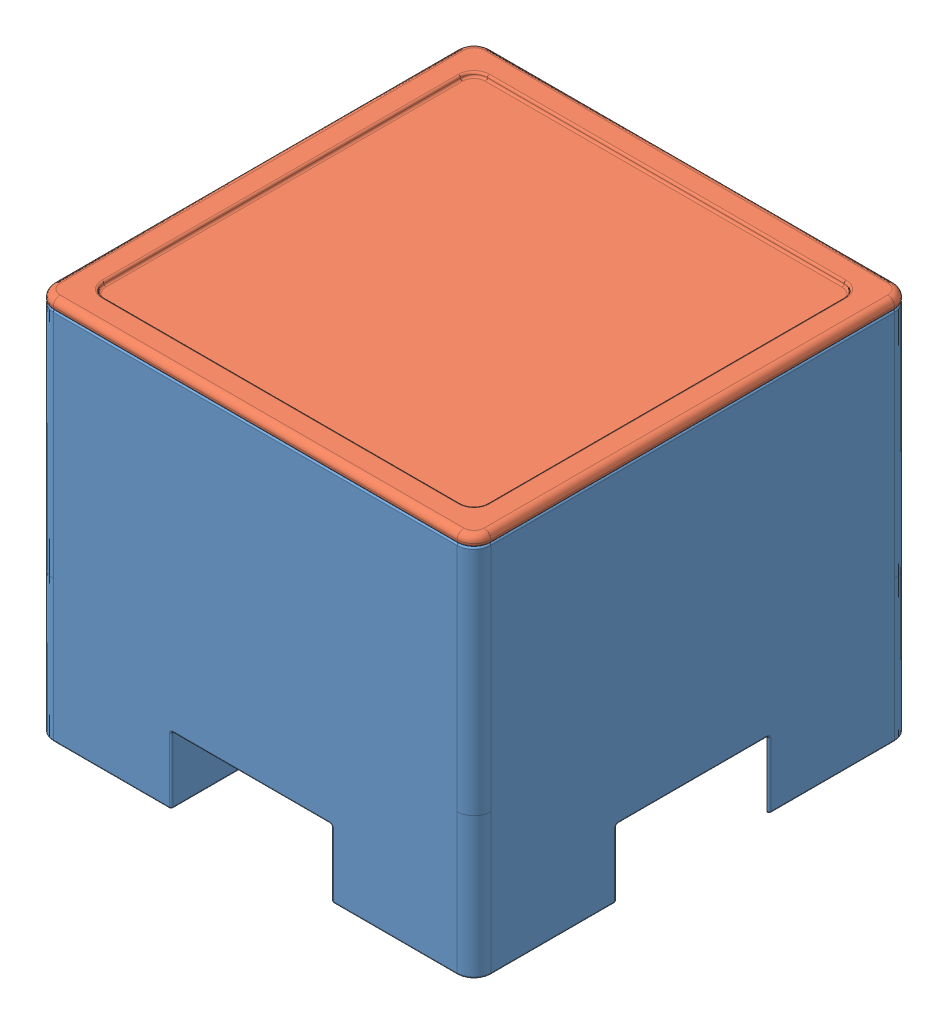
SolidWorks assembly Bloc programme, configuration Défaut. Lengths in mm.
Overall size (65 57 65).
2 component instances, 2 part files, 4 mates.
Components (placement in the parent):
- Blocprog Corps symetrie-1: Blocprog Corps symetrie [Défaut] at (0.5652 5.0087 2.1361) size (65 55.5 65)
- Couvercle-1: Couvercle [Défaut] at (0.5652 39.5087 2.1361) x (1 0 0) z (0 1 0) size (65 65 11.5)
Mates (geometry in assembly coordinates):
- Sur place1: in place: plane of assembly through (0 34.5 0) normal (0 1 0); plane of ? through (0 34.5 0) normal (0 1 0); moOrthogonalPlaneRef_w of assembly through (0 34.5 0) normal (0 1 0); plane of ? through (0 34.5 0) normal (0 0 -1); plane of assembly through (0 34.5 0) normal (0 1 0); line of ? through (-55 0 34.5) axis (0 1 0); plane of Blocprog Corps symetrie-1 through (0.5652 39.5087 2.1361) normal (0 1 0); unknown of Couvercle-1
- Coïncidente1: coincident: plane of Blocprog Corps symetrie-1; plane of Couvercle-1
- Coïncidente2: coincident: moOrthogonalPlaneRef_w of Blocprog Corps symetrie-1 through (0.5652 39.5087 2.1361) normal (0 0 -1); plane of Couvercle-1 through (0.5652 39.5087 2.1361) normal (0 0 -1)
- Coïncidente3: coincident: moOrthogonalPlaneRef_w of Blocprog Corps symetrie-1 through (0.5652 39.5087 2.1361) normal (-1 0 0); plane of Couvercle-1 through (0.5652 39.5087 2.1361) normal (1 0 0)
